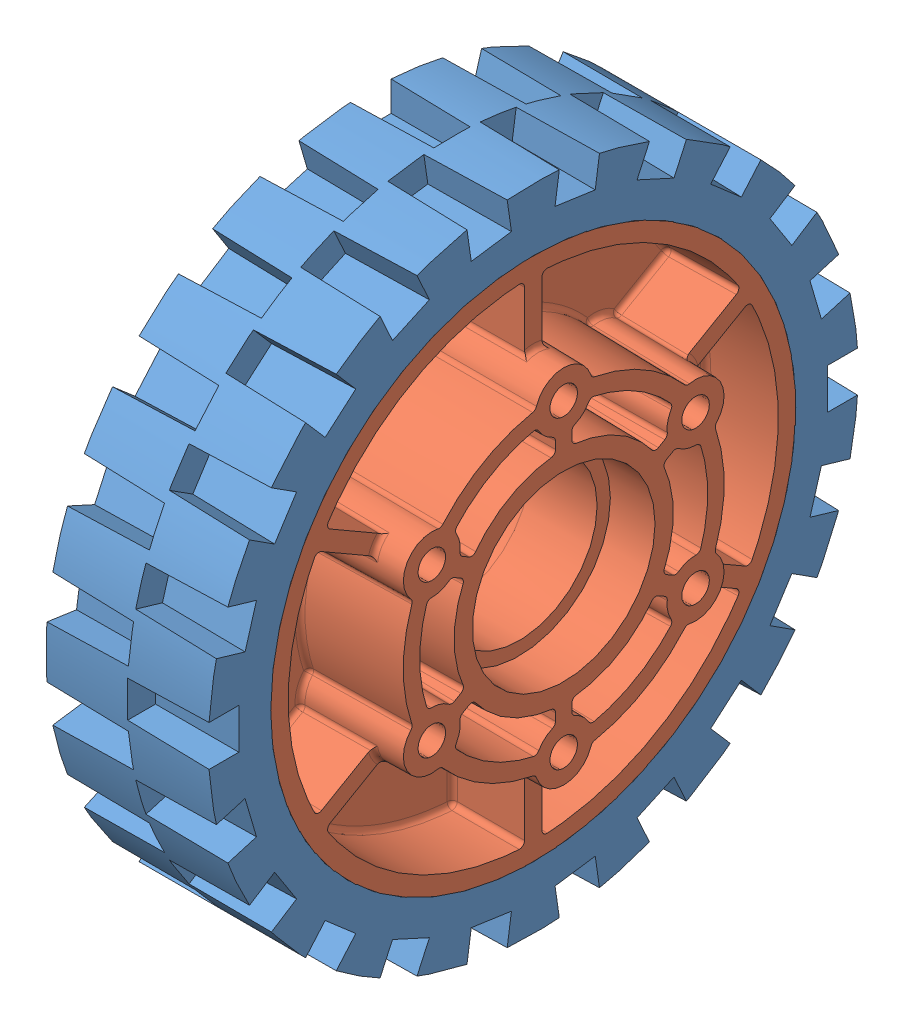
SolidWorks assembly 4in HiGrip Wheel, configuration Default. Lengths in mm.
Overall size (35.12 101.6 101.6).
2 component instances, 2 part files, 0 mates.
Components (placement in the parent):
- 4 in tread-1: 4 in tread [Default] at (-8.0517 2.5236 2.5343) size (25.4 101.6 101.6)
- 4in 2013 Hub-1: 4in 2013 Hub [Default] at (-8.0517 2.5236 2.5343) size (35.12 82.55 82.55)
